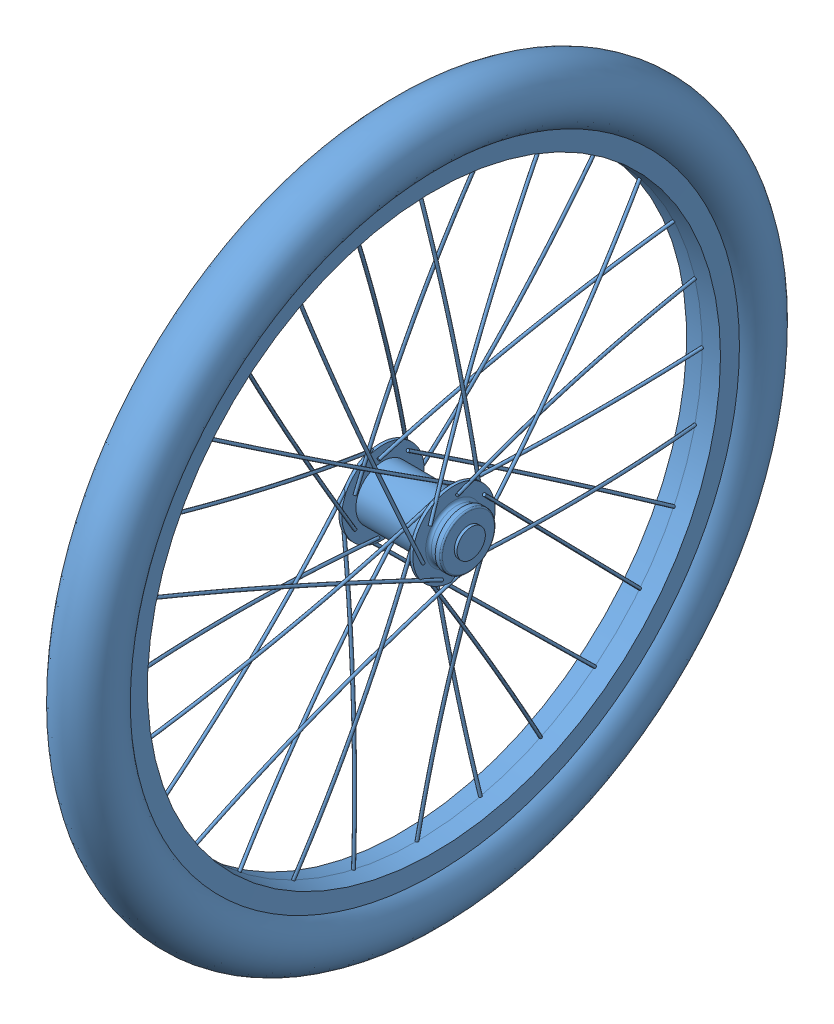
SolidWorks assembly Assy, configuration Default. Lengths in mm.
Overall size (138.78 506.67 506.67).
3 component instances, 3 part files, 1 mates.
Components (placement in the parent):
- TurnigySK8_110kV-2: TurnigySK8_110kV [Default] at (115.3304 100.6697 83.7249) x (0 0 1) z (0 1 0) size (111.2 115.5 62.4) (hidden)
- Wheel-1: Wheel [Default] at origin size (138.78 506.67 506.67)
- Wheel Pulley^Assy-1: Wheel Pulley^Assy [Default] at origin (suppressed, hidden, virtual)
Mates (geometry in assembly coordinates):
- Coincident2: coordinate: point of Wheel-1
